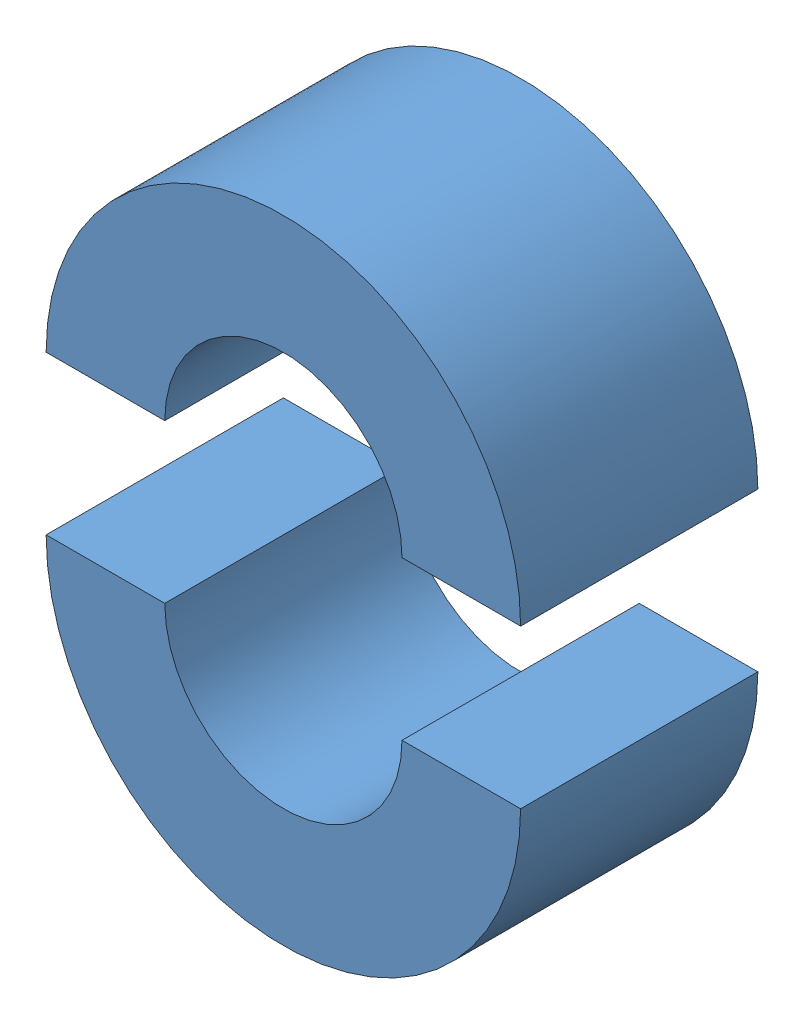
SolidWorks assembly CT-Rings, configuration Default. Lengths in mm.
Overall size (30 40 15).
2 component instances, 1 part files, 3 mates.
Components (placement in the parent):
- CT-Half-1: CT-Half [Default] at (-62.3291 4.3293 20.7028) size (30 15 15)
- CT-Half-2: CT-Half [Default] at (-62.3291 -5.6707 35.7028) x (1 0 0) z (0 0 -1) size (30 15 15)
Mates (geometry in assembly coordinates):
- Coincident1: coincident aligned: plane of CT-Half-1 through (-62.3291 4.3293 35.7028) normal (0 0 1); plane of CT-Half-2 through (-62.3291 -0.6707 35.7028) normal (0 0 1)
- Coincident4: coincident aligned: plane of CT-Half-1 through (-62.3291 4.3293 20.7028) normal (1 0 0); plane of CT-Half-2 through (-62.3291 -0.6707 35.7028) normal (1 0 0)
- Distance1: distance = 10 mm anti-aligned: plane of CT-Half-1 through (-54.8291 4.3293 35.7028) normal (0 -1 0); plane of CT-Half-2 through (-54.8291 -5.6707 20.7028) normal (0 1 0)
